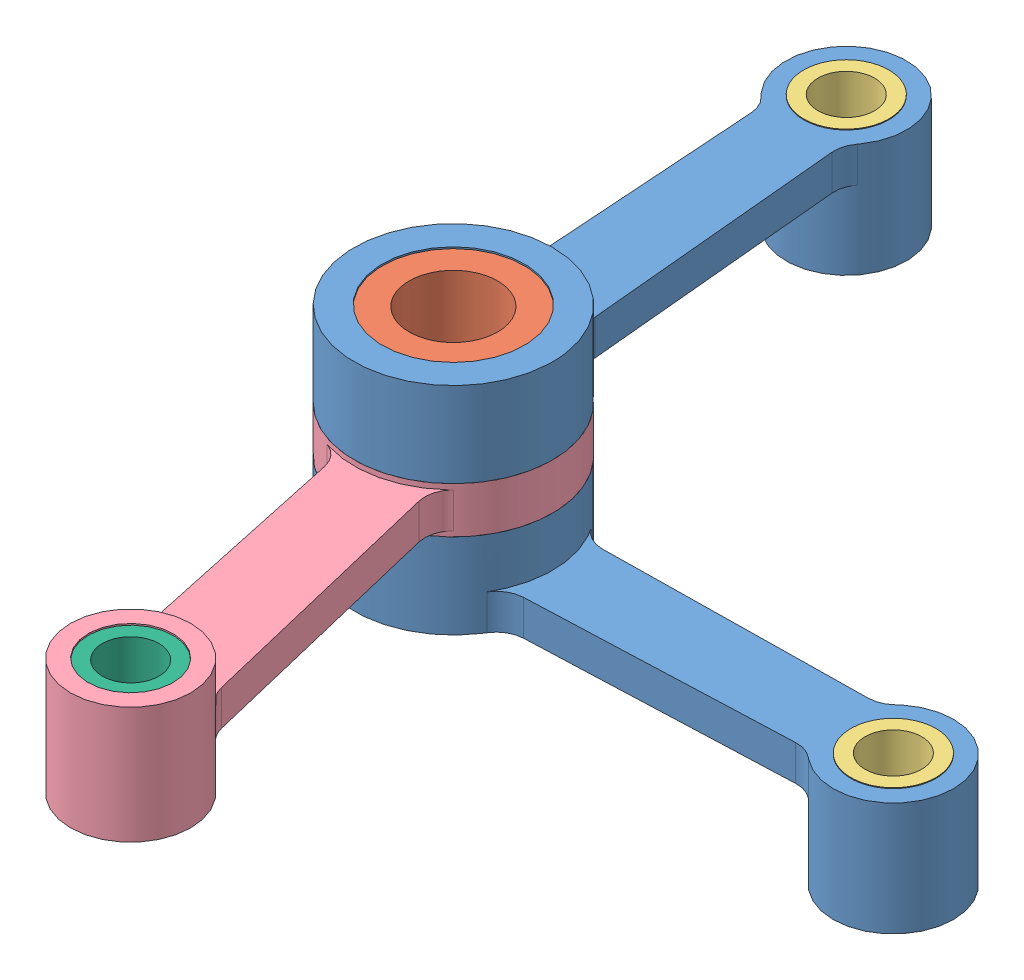
SolidWorks assembly assambly 22,23, configuration Default. Lengths in mm.
Overall size (86.64 41.88 140.01).
12 component instances, 6 part files, 4 mates.
Components (placement in the parent):
- assmbly 23 part-3: assmbly 23 part [Default] at (-3.4068 21.2855 -39.371) size (82.98 23.38 28)
  - 3 p c 23-1: 3 p c 23 [Default] at (17.2456 51.7932 65.1685) size (82.98 23 28)
  - 3 p c 23A-1: 3 p c 23A [Default] at (17.2456 51.5712 65.1685) size (20 12 20)
  - 3 p c 23B-1: 3 p c 23B [Default] at (77.7237 40.4114 63.5434) x (0.916599 0 -0.399808) z (0.399808 0 0.916599) size (12 16.5 12)
- assmbly 22 part-2: assmbly 22 part [Default] at (68.0721 37.0985 -12.4275) x (0.222021 0 0.975042) z (-0.975042 0 0.222021) size (83 16.71 28)
  - 3 p c 22 A-1: 3 p c 22 A [Default] at (25.23 51.2302 61.3665) size (83 16.5 28)
  - 3 p c 22 B-1: 3 p c 22 B [Default] at (25.23 47.9662 61.3665) size (20 6.5 20)
  - 3 p c 22C-1: 3 p c 22C [Default] at (85.73 42.7697 61.3665) size (12 16.5 12)
- assmbly 23 part-4: assmbly 23 part [Default] at (-50.3167 39.7855 46.4957) x (-0.053356 0 -0.998576) z (0.998576 0 -0.053356) size (82.98 23.38 28)
  - 3 p c 23-1: 3 p c 23 [Default] at (17.2456 51.7932 65.1685) size (82.98 23 28)
  - 3 p c 23A-1: 3 p c 23A [Default] at (17.2456 51.5712 65.1685) size (20 12 20)
  - 3 p c 23B-1: 3 p c 23B [Default] at (77.7237 40.4114 63.5434) x (0.916599 0 -0.399808) z (0.399808 0 0.916599) size (12 16.5 12)
Mates (geometry in assembly coordinates):
- Concentric2: concentric aligned: circle of assmbly 23 part-3/3 p c 23A-1; circle of assmbly 22 part-2/3 p c 22 B-1
- Coincident3: coincident anti-aligned: plane of assmbly 23 part-3/3 p c 23-1 through (13.8388 85.0787 25.7975) normal (0 1 0); plane of assmbly 22 part-2/3 p c 22 A-1 through (13.8388 85.0787 25.7975) normal (0 -1 0)
- Concentric3: concentric aligned: circle of assmbly 22 part-2/3 p c 22 B-1; circle of assmbly 23 part-4/3 p c 23A-1
- Coincident5: coincident anti-aligned: plane of assmbly 22 part-2/3 p c 22 A-1 through (13.8388 91.5787 25.7975) normal (0 1 0); plane of assmbly 23 part-4/3 p c 23-1 through (13.8388 91.5787 25.7975) normal (0 -1 0)
